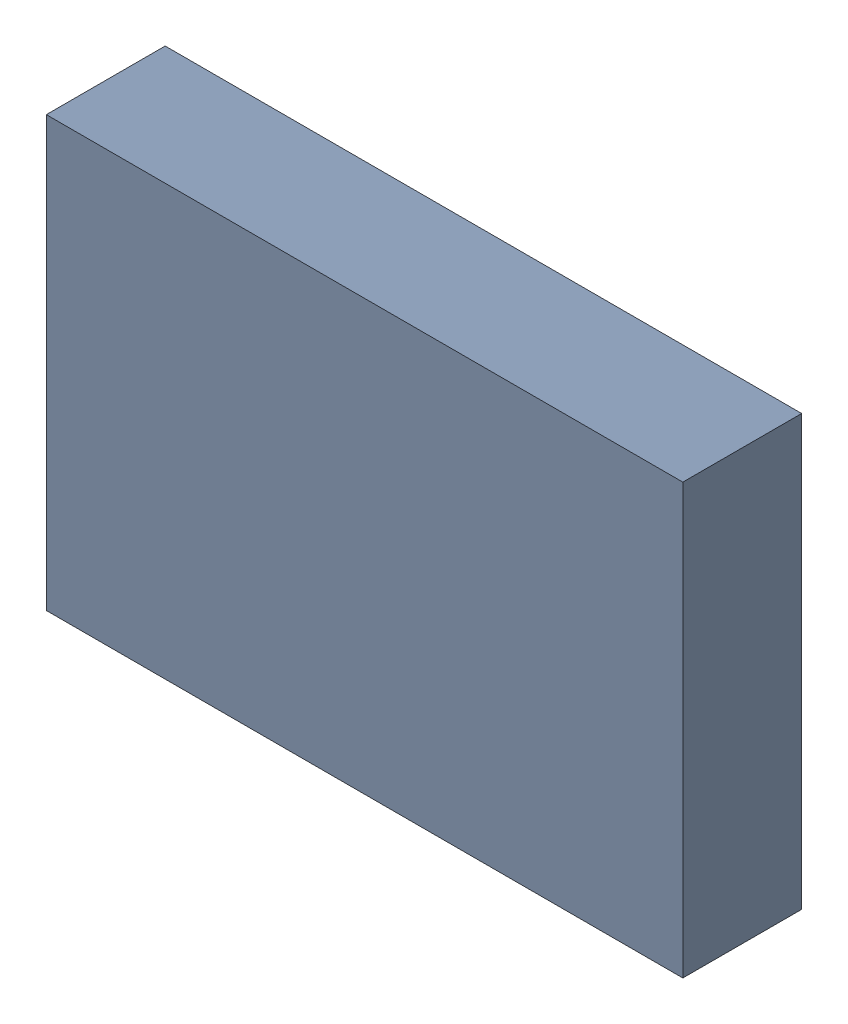
SolidWorks assembly U5, configuration Default. Lengths in mm.
Overall size (8.3 5.6 1.55).
2 component instances, 1 part files, 0 mates.
Components (placement in the parent):
- 575414720-1: 575414720 [Default] at (46.736 21.066 -2.0115) size (8.3 5.6 1.55)
  - Extruded-1: Extruded [Default] at origin size (8.3 5.6 1.55)
